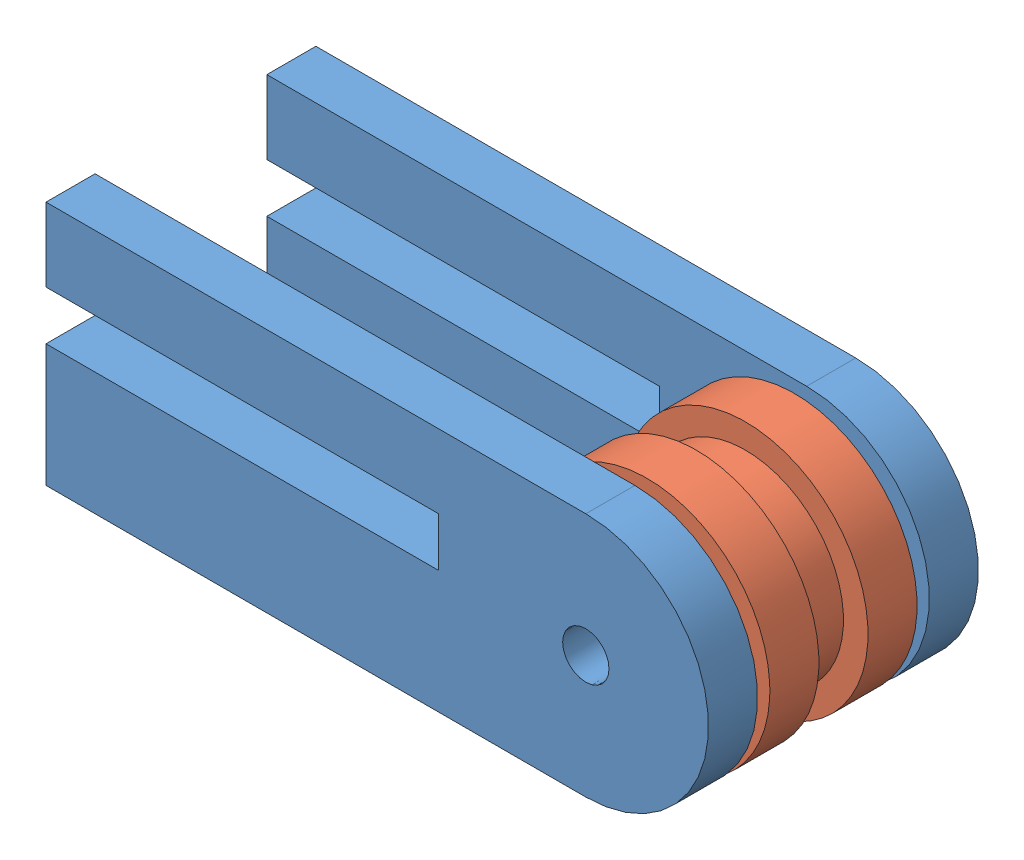
SolidWorks assembly RollerAssembly, configuration Default. Lengths in mm.
Overall size (42.86 15.88 17.46).
5 component instances, 2 part files, 7 mates.
Components (placement in the parent):
- RollerGuide-1: RollerGuide [Default] at (414.8935 127.8779 -81.0958) size (42.86 15.88 3.17)
- RollerGuide-2: RollerGuide [Default] at (414.8935 127.8779 -66.8084) size (42.86 15.88 3.17)
- GuideRollers-1: GuideRollers [Large] at (449.8185 135.8154 -70.7771) size (15.88 15.88 3.17)
- GuideRollers-2: GuideRollers [Large] at (449.8185 135.8154 -77.1271) size (15.88 15.88 3.17)
- GuideRollers-3: GuideRollers [Small] at (449.8185 135.8154 -73.9521) size (12.7 12.7 3.17)
Mates (geometry in assembly coordinates):
- Concentric36: concentric aligned: cylinder of RollerGuide-1 through (449.8185 135.8154 -77.9209) axis (0 0 -1) radius 1.5; cylinder of RollerGuide-2 through (449.8185 135.8154 -63.6334) axis (0 0 -1) radius 1.5
- Concentric39: concentric aligned: cylinder of RollerGuide-1 through (449.8185 135.8154 -77.9209) axis (0 0 -1) radius 1.5; cylinder of GuideRollers-2 through (449.8185 135.8154 -73.9521) axis (0 0 -1) radius 1.5
- Distance54: distance = 0.7937 mm anti-aligned: plane of GuideRollers-1 through (449.8185 135.8154 -67.6021) normal (0 0 1); plane of RollerGuide-2 through (414.8935 127.8779 -66.8084) normal (0 0 -1)
- Concentric37: concentric aligned: cylinder of GuideRollers-1 through (449.8185 135.8154 -67.6021) axis (0 0 -1) radius 1.5; cylinder of GuideRollers-3 through (449.8185 135.8154 -70.7771) axis (0 0 -1) radius 1.5
- Coincident434: coincident anti-aligned: plane of GuideRollers-1 through (449.8185 135.8154 -70.7771) normal (0 0 -1); plane of GuideRollers-3 through (449.8185 135.8154 -70.7771) normal (0 0 1)
- Coincident435: coincident anti-aligned: plane of GuideRollers-2 through (449.8185 135.8154 -73.9521) normal (0 0 1); plane of GuideRollers-3 through (449.8185 135.8154 -73.9521) normal (0 0 -1)
- Concentric38: concentric aligned: circle of GuideRollers-2; circle of GuideRollers-3
